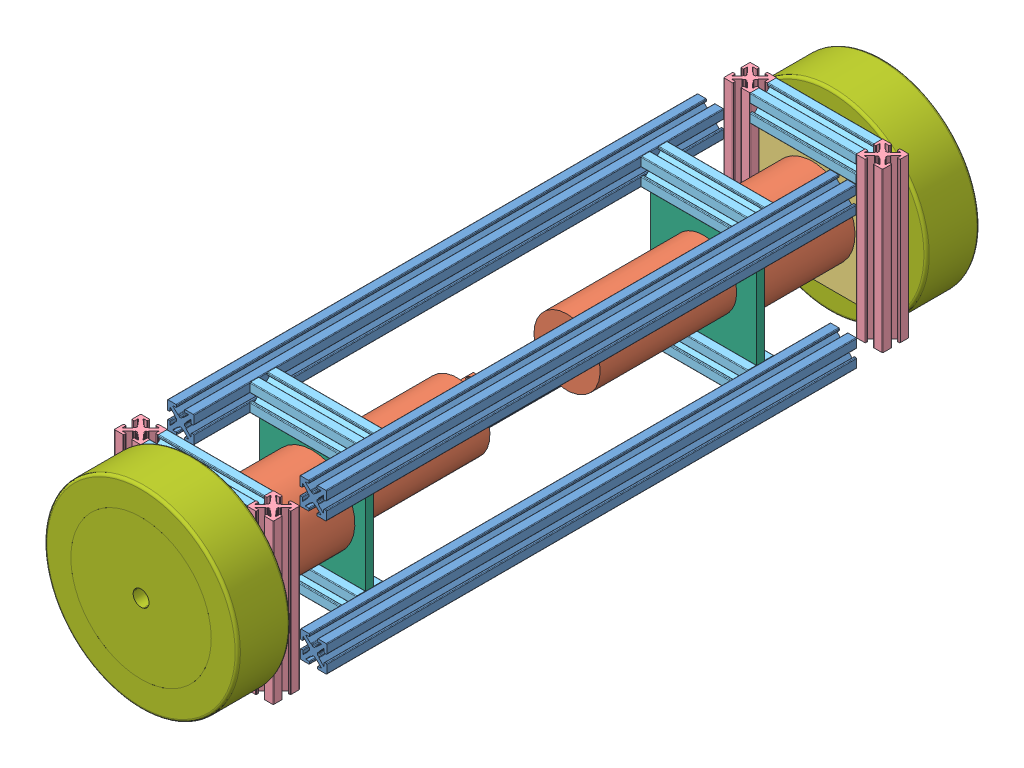
SolidWorks assembly bloc moteur, configuration Défaut. Lengths in mm.
Overall size (73 73 280.02).
22 component instances, 7 part files, 27 mates.
Components (placement in the parent):
- entretoise3-1: entretoise3 [Default] at (-26.7957 34.6029 -160.8024) x (0 0 1) z (-1 0 0) size (200 10.01 10.01)
- moteur-1: moteur [Défaut] at (-1.6995 9.6915 14.5) x (0 -1 0) z (0 0 1) size (32 32 128.4)
- fix moteur-2: fix moteur [Défaut] at (-1.4048 22.9734 55.7) x (0 1 0) z (0 0 -1) size (44.8 44.8 3)
- entretoise1-1: entretoise1 [Default] at (23.2043 39.7915 54.2014) x (0 -1 0) z (0 0 1) size (60 10.01 10.01)
- entretoise1-4: entretoise1 [Default] at (-26.8033 39.7915 54.2014) x (0 -1 0) z (0 0 1) size (60 10.01 10.01)
- entretoise2-2: entretoise2 [Default] at (18.2005 34.7877 54.2014) x (-1 0 0) z (0 0 1) size (40 10.01 10.01)
- moteur-3: moteur [Défaut] at (-1.6995 9.6915 -136.1048) x (0 1 0) z (0 0 -1) size (32 32 128.4)
- entretoise1-3: entretoise1 [Default] at (23.2043 39.7915 -175.8062) x (0 -1 0) z (0 0 1) size (60 10.01 10.01)
- entretoise2-3: entretoise2 [Default] at (18.2005 34.7877 -175.8062) x (-1 0 0) z (0 0 1) size (40 10.01 10.01)
- fix moteur-3: fix moteur [Défaut] at (-1.4048 22.9734 -174.3048) x (0 1 0) z (0 0 -1) size (44.8 44.8 3)
- entretoise3-5: entretoise3 [Default] at (23.2119 34.7877 -160.8024) x (0 0 1) z (0 1 0) size (200 10.01 10.01)
- entretoise3-6: entretoise3 [Default] at (23.3967 -15.2199 -160.8024) x (0 0 1) z (1 0 0) size (200 10.01 10.01)
- entretoise3-7: entretoise3 [Default] at (-26.6109 -15.4047 -160.8024) x (0 0 1) z (0 -1 0) size (200 10.01 10.01)
- entretoise2-5: entretoise2 [Default] at (18.2081 34.6029 13.0014) x (-1 0 0) z (0 0 -1) size (40 10.01 10.01)
- entretoise2-6: entretoise2 [Default] at (-21.6071 -15.2199 13.0014) size (40 10.01 10.01)
- fix moteur 2-1: fix moteur 2 [Défaut] at (8.9391 16.2303 11.5) size (40 44.8 3)
- entretoise2-7: entretoise2 [Default] at (18.2081 34.6029 -134.6062) x (-1 0 0) z (0 0 -1) size (40 10.01 10.01)
- fix moteur 2-3: fix moteur 2 [Défaut] at (8.9391 16.2303 -136.1048) size (40 44.8 3)
- entretoise2-8: entretoise2 [Default] at (-21.6071 -15.2199 -134.6062) size (40 10.01 10.01)
- Roue-1: Roue [Défaut] at (-1.6995 9.6915 59.2052) size (73 73 20)
- Roue-2: Roue [Défaut] at (-1.6995 9.6915 -200.81) size (73 73 20)
- entretoise1-5: entretoise1 [Default] at (-26.8033 39.7915 -175.8062) x (0 -1 0) z (0 0 1) size (60 10.01 10.01)
Mates (geometry in assembly coordinates):
- Coaxiale4: concentric anti-aligned: cylinder of moteur-1 through (11.3005 9.6915 48.7) axis (0 0 1) radius 1.5; cylinder of fix moteur-2 through (11.3005 9.6915 55.7) axis (0 0 -1) radius 1.5
- Coaxiale5: concentric aligned: cylinder of moteur-1 through (-1.6995 9.6915 55.7) axis (0 0 -1) radius 10; cylinder of fix moteur-2 through (-1.6995 9.6915 55.7) axis (0 0 -1) radius 10
- Coïncidente5: coincident anti-aligned: plane of moteur-1 through (-1.6995 9.6915 52.7) normal (0 0 1); plane of fix moteur-2 through (-24.0995 -12.7085 52.7) normal (0 0 -1)
- Coïncidente8: coincident anti-aligned: plane of fix moteur-2 through (-24.0995 -12.7085 55.7) normal (0 0 1); plane of entretoise1-1 through (18.9371 -20.2085 55.7) normal (0 0 -1)
- Distance2: distance = 2.5 mm anti-aligned: plane of fix moteur-2 through (20.7005 -12.7085 52.7) normal (1 0 0); plane of entretoise1-1 through (18.2005 -20.2085 55.954) normal (-1 0 0)
- Distance4: distance = 7.5 mm aligned: plane of entretoise1-1 through (27.0905 -20.2085 51.3976) normal (0 -1 0); plane of fix moteur-2 through (20.7005 -12.7085 52.7) normal (0 -1 0)
- Coïncidente17: coincident anti-aligned: plane of entretoise1-1 through (18.2005 -20.2085 55.954) normal (-1 0 0); plane of entretoise2-2 through (18.2005 30.9015 51.3976) normal (1 0 0)
- Coïncidente18: coincident aligned: plane of entretoise1-1 through (27.0905 39.7915 51.3976) normal (0 1 0); plane of entretoise2-2 through (-21.7995 39.7915 55.954) normal (0 1 0)
- Coïncidente19: coincident aligned: plane of entretoise1-1 through (21.4517 -20.2085 59.2052) normal (0 0 1); plane of entretoise2-2 through (-21.7995 36.5403 59.2052) normal (0 0 1)
- Coïncidente25: coincident anti-aligned: plane of entretoise3-6 through (18.3929 -16.9725 39.1976) normal (-1 0 0); plane of entretoise2-6 through (18.3929 -11.3337 10.1976) normal (1 0 0)
- Coïncidente26: coincident aligned: plane of entretoise3-6 through (21.6441 -10.2161 39.1976) normal (0 1 0); plane of entretoise2-6 through (18.3929 -10.2161 14.754) normal (0 1 0)
- Coaxiale8: concentric anti-aligned: cylinder of moteur-1 through (-1.6995 9.6915 -40) axis (0 0 1) radius 12.5; cylinder of fix moteur 2-1 through (-1.6995 9.6915 14.5) axis (0 0 -1) radius 12.5
- Coïncidente27: coincident anti-aligned: plane of moteur-1 through (-1.6995 9.6915 14.5) normal (0 0 -1); plane of fix moteur 2-1 through (-21.6995 -12.7085 14.5) normal (0 0 1)
- Coïncidente29: coincident anti-aligned: plane of entretoise2-6 through (18.3929 -10.9527 14.5) normal (0 0 -1); plane of fix moteur 2-1 through (-21.6995 -12.7085 14.5) normal (0 0 1)
- Coaxiale9: concentric aligned: cylinder of moteur-1 through (-1.6995 9.6915 72.7) axis (0 0 -1) radius 3; cylinder of Roue-1 through (-1.6995 9.6915 59.2052) axis (0 0 -1) radius 3
- Coïncidente31: coincident anti-aligned: plane of entretoise1-1 through (21.4517 -20.2085 59.2052) normal (0 0 1); plane of Roue-1 through (-1.6995 9.6915 59.2052) normal (0 0 -1)
- Coïncidente35: coincident anti-aligned: plane of entretoise3-1 through (-21.7919 36.3555 39.1976) normal (1 0 0); plane of entretoise2-5 through (-21.7919 38.4891 15.8052) normal (-1 0 0)
- Coïncidente36: coincident aligned: plane of entretoise3-1 through (-25.0431 39.6067 39.1976) normal (0 1 0); plane of entretoise2-5 through (-21.7919 39.6067 11.2488) normal (0 1 0)
- Coïncidente37: coincident anti-aligned: plane of entretoise2-5 through (-21.7919 30.3357 14.5) normal (0 0 -1); plane of fix moteur 2-1 through (-21.6995 -12.7085 14.5) normal (0 0 1)
- Coïncidente38: coincident aligned: plane of entretoise3-1 through (-25.0431 39.6067 39.1976) normal (0 1 0); plane of entretoise2-5 through (-21.7919 39.6067 14.754) normal (0 1 0)
- Coïncidente39: coincident anti-aligned: plane of entretoise3-7 through (-21.6071 -17.1573 39.1976) normal (1 0 0); plane of entretoise2-6 through (-21.6071 -11.3337 10.1976) normal (-1 0 0)
- Distance5: distance = 10 mm anti-aligned: plane of entretoise3-5 through (27.0981 31.9839 39.1976) normal (0 0 1); plane of entretoise1-1 through (24.9569 -20.2085 49.1976) normal (0 0 -1)
- Coïncidente42: coincident aligned: plane of entretoise1-1 through (27.0905 39.7915 51.3976) normal (0 1 0); plane of entretoise3-5 through (24.9645 39.7915 39.1976) normal (0 1 0)
- Coïncidente43: coincident aligned: plane of entretoise1-4 through (-22.9171 39.7915 51.3976) normal (0 1 0); plane of entretoise2-2 through (-21.7995 39.7915 52.4488) normal (0 1 0)
- Coïncidente44: coincident aligned: plane of entretoise1-4 through (-25.0507 -20.2085 59.2052) normal (0 0 1); plane of entretoise2-2 through (-21.7995 36.5403 59.2052) normal (0 0 1)
- Coïncidente45: coincident anti-aligned: plane of entretoise1-4 through (-21.7995 -20.2085 55.954) normal (1 0 0); plane of entretoise2-2 through (-21.7995 30.9015 51.3976) normal (-1 0 0)
- PLAN1: unknown: plane of entretoise3-1 through (-23.992 38.4891 39.1976) normal (0 0 1); plane of entretoise3-1 through (-23.992 38.4891 -160.8024) normal (0 0 -1)
